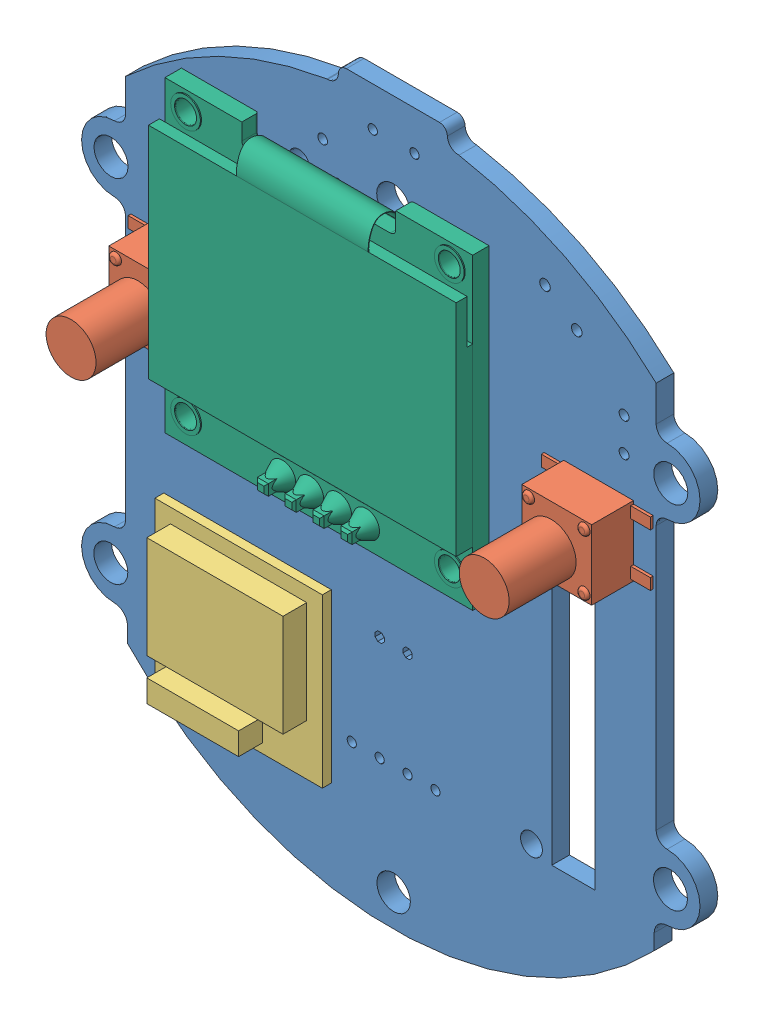
SolidWorks assembly PCB_Final, configuration Default. Lengths in mm.
Overall size (56.29 65.69 17.53).
7 component instances, 6 part files, 16 mates.
Components (placement in the parent):
- JDL_PCB_From_Eagle-1: JDL_PCB_From_Eagle [Default] at (-7.6824 -3.0353 2.7693) size (56.29 65.69 1.61)
- JDL_95C06F3GWT_TactSwitch-1: JDL_95C06F3GWT_TactSwitch [Default] at (-26.1821 9.2553 4.3822) x (-1 0 0) z (0 1 0) size (9.93 10.41 6.35)
- JDL_95C06F3GWT_TactSwitch-2: JDL_95C06F3GWT_TactSwitch [Default] at (11.4099 9.2553 4.3822) x (-1 0 0) z (0 1 0) size (9.93 10.41 6.35)
- JDL_RFDuino-1: JDL_RFDuino [Default] at (-20.5361 -15.9626 4.3822) x (1 0 0) z (0 -1 0) size (15.24 2.97 15.24)
- JDL_JST_Female-1: JDL_JST_Female [Default] at (-11.5107 14.455 -0.5307) x (0 -1 0) z (1 0 0) size (7.9 5.5 7.6)
- JDL_Inductor-1: JDL_Inductor [Default] at (-5.5489 20.3469 4.3822) x (1 0 0) z (0 -1 0) size (5.3 4.5 5.8)
- OLED_NoOffset-1: OLED_NoOffset [Default] at (-7.7274 16.7735 9.2082) x (1 0 0) z (0 -1 0) size (28 12 28)
Mates (geometry in assembly coordinates):
- Distance1: distance = 2.6289 mm aligned: plane of JDL_95C06F3GWT_TactSwitch-1 through (-23.0071 6.0803 8.1922) normal (0 -1 0); plane of JDL_PCB_From_Eagle-1 through (-7.9931 3.4514 4.3822) normal (0 -1 0)
- Coincident13: coincident aligned: plane of JDL_95C06F3GWT_TactSwitch-1 through (-23.0071 6.0803 8.1922) normal (0 -1 0); plane of JDL_95C06F3GWT_TactSwitch-2 through (14.5849 6.0803 8.1922) normal (0 -1 0)
- Distance3: distance = 31.242 mm anti-aligned: plane of JDL_95C06F3GWT_TactSwitch-2 through (8.2349 12.4303 8.1922) normal (-1 0 0); plane of JDL_95C06F3GWT_TactSwitch-1 through (-23.0071 12.4303 8.1922) normal (1 0 0)
- Coincident14: coincident anti-aligned: plane of JDL_PCB_From_Eagle-1 through (-7.9931 -77.5824 4.3822) normal (0 0 1); plane of JDL_RFDuino-1 through (-12.9161 -8.3426 4.3822) normal (0 0 -1)
- Distance4: distance = 20.066 mm aligned: plane of JDL_PCB_From_Eagle-1 through (7.1499 -77.5824 4.3822) normal (1 0 0); plane of JDL_RFDuino-1 through (-12.9161 -23.5826 5.195) normal (1 0 0)
- Distance5: distance = 3.556 mm anti-aligned: plane of JDL_RFDuino-1 through (-28.1561 -23.5826 5.195) normal (0 -1 0); plane of JDL_PCB_From_Eagle-1 through (-7.9931 -20.0266 4.3822) normal (0 1 0)
- Coincident20: coincident anti-aligned: plane of JDL_PCB_From_Eagle-1 through (-7.9931 -77.5824 4.3822) normal (0 0 1); plane of JDL_Inductor-1 through (-2.8989 23.2469 4.3822) normal (0 0 -1)
- Distance8: distance = 10.16 mm aligned: plane of JDL_Inductor-1 through (-8.1989 23.2469 4.8822) normal (0 1 0); plane of JDL_PCB_From_Eagle-1 through (-7.9931 33.4069 4.3822) normal (0 1 0)
- Distance9: distance = 23.4442 mm aligned: plane of JDL_Inductor-1 through (-8.1989 17.4469 4.8822) normal (-1 0 0); plane of JDL_PCB_From_Eagle-1 through (-31.6431 -77.5824 4.3822) normal (-1 0 0)
- Coincident24: coincident anti-aligned: plane of JDL_PCB_From_Eagle-1 through (-7.9931 -77.5824 4.3822) normal (0 0 1); plane of JDL_95C06F3GWT_TactSwitch-1 through (-29.3571 6.0803 4.3822) normal (0 0 -1)
- Coincident25: coincident anti-aligned: plane of JDL_PCB_From_Eagle-1 through (-7.9931 -77.5824 4.3822) normal (0 0 1); plane of JDL_95C06F3GWT_TactSwitch-2 through (8.2349 6.0803 4.3822) normal (0 0 -1)
- Distance11: distance = 2.286 mm aligned: plane of JDL_95C06F3GWT_TactSwitch-1 through (-29.3571 12.4303 8.1922) normal (-1 0 0); plane of JDL_PCB_From_Eagle-1 through (-31.6431 -77.5824 4.3822) normal (-1 0 0)
- Distance12: distance = 4.826 mm anti-aligned: plane of OLED_NoOffset-1 through (-1.2274 29.2735 9.2082) normal (0 0 -1); plane of JDL_PCB_From_Eagle-1 through (-7.9931 -77.5824 4.3822) normal (0 0 1)
- Parallel1: parallel aligned: plane of JDL_PCB_From_Eagle-1 through (-7.9931 3.4514 4.3822) normal (0 -1 0); plane of OLED_NoOffset-1 through (-21.7274 2.7735 10.7082) normal (0 -1 0)
- Coincident29: coincident anti-aligned: plane of JDL_PCB_From_Eagle-1 through (-7.9931 -77.5824 2.7693) normal (0 0 -1); plane of JDL_JST_Female-1 through (-11.5107 6.555 2.7693) normal (0 0 1)
- Parallel2: parallel aligned: plane of JDL_PCB_From_Eagle-1 through (-31.6431 -77.5824 4.3822) normal (-1 0 0); plane of JDL_JST_Female-1 through (-17.5107 6.555 -0.5307) normal (-1 0 0)
